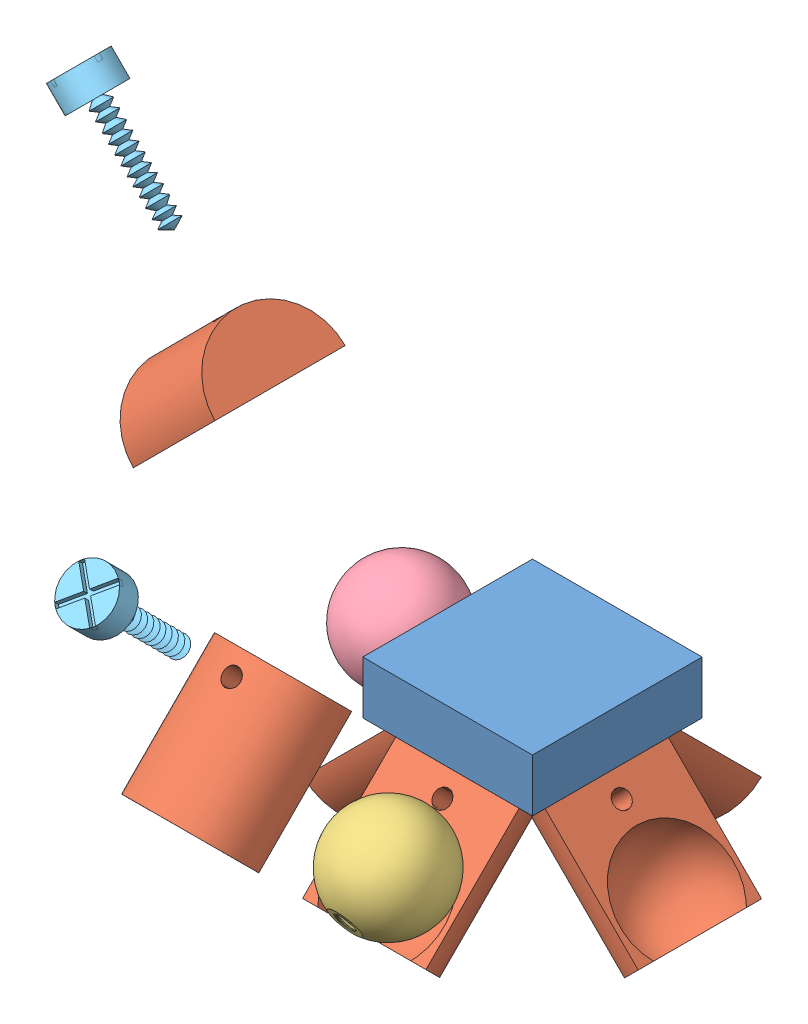
SolidWorks assembly Ensamblaje3, configuration Predeterminado. Lengths in mm.
Overall size (120.83 95.43 120.62).
12 component instances, 5 part files, 4 mates.
Components (placement in the parent):
- Acople final-1: Acople final [Predeterminado] at (3.8446 -3.4751 15.1546) size (63.12 37.79 63.25)
  - Base final-1: Base final [Predeterminado] at (22.7654 1.2928 32) size (32 22.43 32)
  - Cilindro de base 4 puntos_6-1: Cilindro de base 4 puntos_6 [Predeterminado] at (-16.7159 -5.7926 20.8119) x (0 -0.707107 -0.707107) z (1 0 0) size (24.84 11.63 23.26)
  - Cilindro de base 4 puntos_6-2: Cilindro de base 4 puntos_6 [Predeterminado] at (-43.918 -5.7769 48) x (-0.707107 -0.707107 0) z (0 0 -1) size (24.84 11.63 23.26)
  - Cilindro de base 4 puntos_6-3: Cilindro de base 4 puntos_6 [Predeterminado] at (10.5151 -5.748 48) x (0.707107 -0.707107 0) z (0 0 1) size (24.84 11.63 23.26)
  - Cilindro de base 4 puntos_6-4: Cilindro de base 4 puntos_6 [Predeterminado] at (-16.7159 -5.6015 75.3793) x (0 -0.707107 0.707107) z (-1 0 0) size (24.84 11.63 23.26)
- Cilindro de base 4 puntos_6-1: Cilindro de base 4 puntos_6 [Predeterminado] at (-12.8415 22.4985 122.1089) x (0.002033 -0.707105 0.707105) z (0.999998 0.001438 -0.001438) size (24.84 11.63 23.26)
- esfera rosca chica-1: esfera rosca chica [Predeterminado] at (-6.2613 4.0758 93.1592) x (0.748179 0.565808 0.346538) z (0.663495 -0.639244 -0.388769) size (20 19.88 20)
- esfera rosca grande-1: esfera rosca grande [Predeterminado] at (-38.4322 4.9085 56.1255) x (-0.17853 0.436146 0.881988) z (0.351563 -0.808942 0.471187) size (20 17.92 20)
- Cilindro de base 4 puntos_6-2: Cilindro de base 4 puntos_6 [Predeterminado] at (-73.304 24.0538 61.9051) x (-0.704548 -0.704548 -0.085001) z (-0.060105 -0.060105 0.996381) size (24.84 11.63 23.26)
- Tornillo-1: Tornillo [Predeterminado] at (-7.4177 51.3572 137.8913) x (0 0.707107 0.707107) z (-0.707107 -0.5 0.5) size (25.46 10.2 10.24)
- Tornillo-2: Tornillo [Predeterminado] at (-85.2276 56.9093 55.4435) x (-0.707107 0.707107 0) z (0.706965 0.706965 0.020012) size (25.46 10.2 10.24)
Mates (geometry in assembly coordinates):
- Coincidente2: coincident anti-aligned: cylinder of Acople final-1/Cilindro de base 4 puntos_6-4 through (-12.8714 -34.0374 44.7841) axis (0 0.707107 0.707107) radius 1.65; circle of Cilindro de base 4 puntos_6-1
- Coincidente4: coincident anti-aligned: cylinder of Acople final-1/Cilindro de base 4 puntos_6-2 through (5.6763 -34.2129 63.1546) axis (-0.707107 0.707107 0) radius 1.65; circle of Cilindro de base 4 puntos_6-2
- Concéntrica5: concentric aligned: cylinder of Cilindro de base 4 puntos_6-1 through (-12.8714 68.2483 147.0698) axis (0 -0.707107 -0.707107) radius 1.65; circle of Tornillo-1
- Concéntrica6: concentric aligned: cylinder of Cilindro de base 4 puntos_6-2 through (-98.3025 69.766 63.1546) axis (0.707107 -0.707107 0) radius 1.65; circle of Tornillo-2
